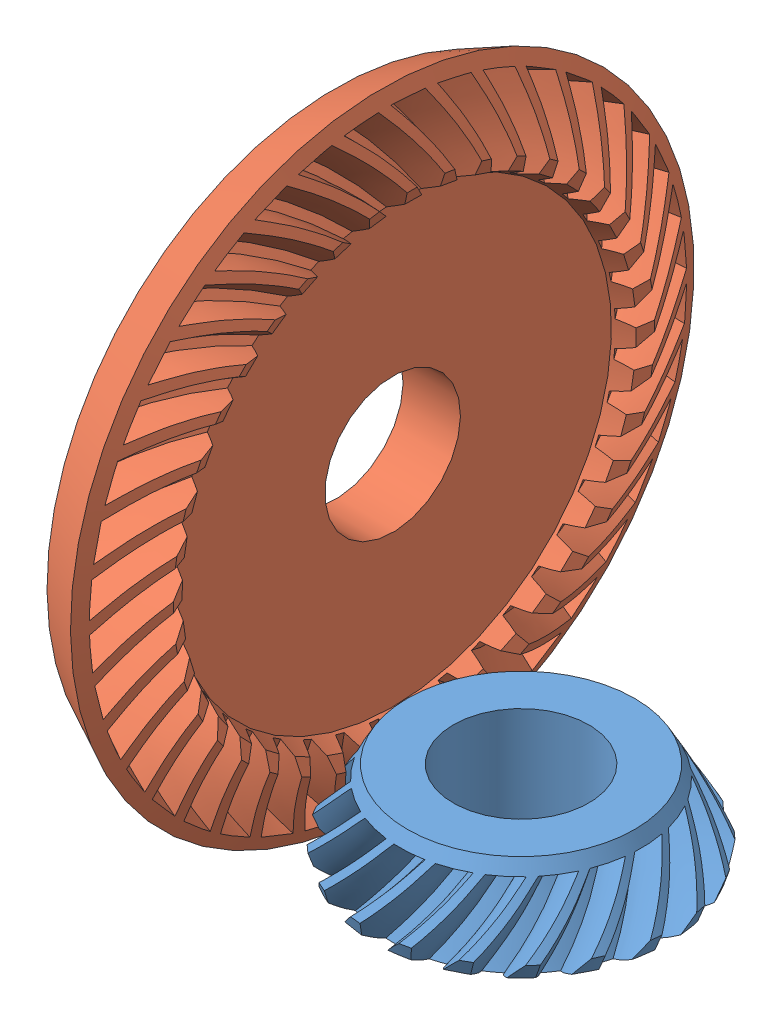
SolidWorks assembly Helical Bevel Test Assembly, configuration Default. Lengths in mm.
Overall size (129.34 76.29 120.75).
2 component instances, 2 part files, 2 mates.
Components (placement in the parent):
- Helical Inner Bevel Gear-1: Helical Inner Bevel Gear [Default] at origin size (77.34 38.67 30.94)
- Helical Outer Bevel Gear-1: Helical Outer Bevel Gear [Default] x (0 -0.996831 0.079543) z (0 0.079543 0.996831) size (60.69 118.21 116.29)
Mates (geometry in assembly coordinates):
- Coincident1: coincident aligned: line of Helical Inner Bevel Gear-1 through (63.5 0 0) axis (0 -1 0); line of Helical Outer Bevel Gear-1 through (0 0 0) axis (-1 0 0)
- Coincident2: coincident: point of Helical Inner Bevel Gear-1; point of Helical Outer Bevel Gear-1
